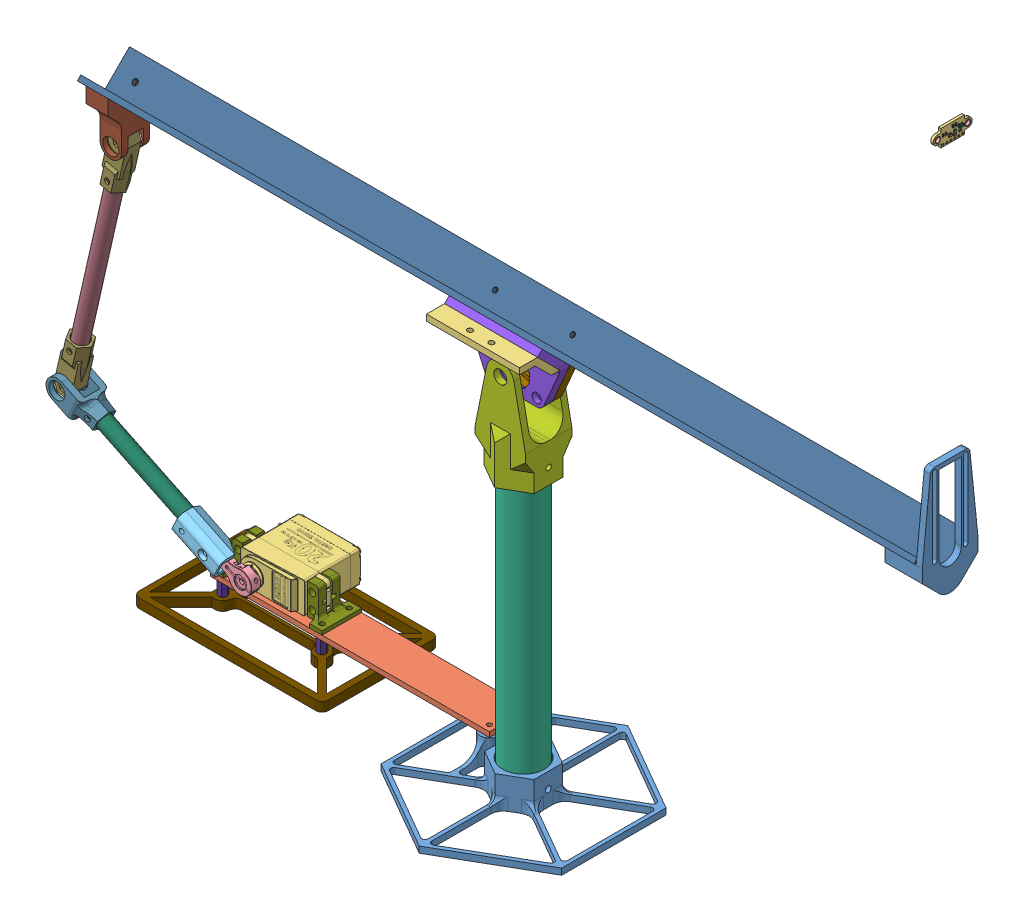
SolidWorks assembly Sistema_barra_bola, configuration Predeterminado. Lengths in mm.
Overall size (579.67 513.66 134.64).
52 component instances, 39 part files, 56 mates.
Components (placement in the parent):
- Soporte_base-1: Soporte_base [Predeterminado] at (0.7319 45.2828 116.0405) x (0 0 1) z (1 0 0) size (134.64 20.58 116.6)
- platina-1: platina [Predeterminado] at (-115.2681 61.2828 99.3405) size (180 3.17 25.4)
- DS3218MG MS24 Digital Servo 270-1: DS3218MG MS24 Digital Servo 270 [Default] at (-179.2681 74.4678 97.7405) x (0 1 0) z (1 0 0) size (20.1 45.99 55.6)
- Servo Arm for DS3218MG-1: Servo Arm for DS3218MG [Default] at (-179.2681 74.4678 118.9404) x (-0.43387 -0.900976 0) z (-0.900976 0.43387 0) size (14.5 6.15 35.53)
- brazo_servo_acople-1: brazo_servo_acople [Predeterminado] at (-206.7479 87.7008 116.0404) x (-0.43387 -0.900976 0) z (0 0 1) size (14.32 30 14.8)
- Tubo_soporte-1: Tubo_soporte [Predeterminado] at (0.7319 45.2828 116.0405) x (0 0 1) z (-1 0 0) size (25.4 200 25.4)
- Articulacion_eje-1: Articulacion_eje [Predeterminado] at (0.7319 250.2828 116.0405) x (0 0 1) z (-1 0 0) size (37.41 69 32.4)
- Soporte_barra_frontal-1: Soporte_barra_frontal [Predeterminado] at (0.7319 299.2828 116.0405) x (1 0 0) z (0 -1 0) size (60 20.96 45.96)
- Soporte_barra_posterior-1: Soporte_barra_posterior [Predeterminado] at (0.7319 299.2828 116.0405) x (-1 0 0) z (0 -1 0) size (60 20.96 45.96)
- Barra-1: Barra [Predeterminado] at (0.7319 299.2828 116.0405) x (1 0 0) z (0 0.707107 0.707107) size (540 25.4 25.4)
- acople_rodamiento_barra-1: acople_rodamiento_barra [Predeterminado] at (-256.5681 282.3833 116.0404) x (0 0 -1) z (1 0 0) size (35.92 41.86 14)
- acople_brazo-1: acople_brazo [Predeterminado] at (-256.5681 282.3833 116.0404) x (0 0 1) z (0.975277 -0.220985 0) size (12.4 33.8 14.32)
- brazo2-1: brazo2 [Predeterminado] at (-287.263 146.9173 116.0404) x (0 0 -1) z (0.975277 -0.220985 0) size (9 120 9)
- acople_brazos-1: acople_brazos [Predeterminado] at (-286.9347 126.3152 116.0404) x (0 0 -1) z (-0.43387 -0.900976 0) size (18 31 14)
- acople_brazo-2: acople_brazo [Predeterminado] at (-291.4396 128.4845 116.0404) x (0 0 -1) z (0.975277 -0.220985 0) size (12.4 33.8 14.32)
- brazo-100mm-1: brazo-100mm [Predeterminado] at (-278.8259 122.4104 116.0404) x (0 0 1) z (0.43387 0.900976 0) size (9 80 9)
- Soporte_servo-1: Soporte_servo [Predeterminado] at (-143.2681 64.4678 99.3404) x (1 0 0) z (0 0 1) size (15 20 25.4)
- Soporte_servo-2: Soporte_servo [Predeterminado] at (-195.2681 64.4678 99.3405) x (-1 0 0) z (0 0 -1) size (15 20 25.4)
- M3_F_TO_F_10MM_STANDOFF.step-1: M3_F_TO_F_10MM_STANDOFF.step [Predeterminado] at (-137.2681 56.2828 108.0405) x (1 0 0) z (0 -1 0) size (5.78 5.78 10)
- M3_F_TO_F_10MM_STANDOFF.step-2: M3_F_TO_F_10MM_STANDOFF.step [Predeterminado] at (-201.2681 56.2828 90.6405) x (1 0 0) z (0 -1 0) size (5.78 5.78 10)
- M3_F_TO_F_10MM_STANDOFF.step-3: M3_F_TO_F_10MM_STANDOFF.step [Predeterminado] at (-137.2681 56.2828 90.6405) x (1 0 0) z (0 -1 0) size (5.78 5.78 10)
- M3_F_TO_F_10MM_STANDOFF.step-4: M3_F_TO_F_10MM_STANDOFF.step [Predeterminado] at (-201.2681 56.2828 108.0405) x (1 0 0) z (0 -1 0) size (5.78 5.78 10)
- base_servo-1: base_servo [Predeterminado] at (-169.2681 45.2828 99.3405) size (122 6 75.4)
- Soporte_sensor-1: Soporte_sensor [Predeterminado] at (272.0319 299.2828 116.0405) x (0 0 -1) z (1 0 0) size (35.92 75.1 24)
- VL53L0X_TOF.step-1: VL53L0X_TOF.step [Predeterminado] at (276.0819 553.4878 116.0405) x (0 0 1) z (-1 0 0) size (25.2 10.9 3.8)
  - Trous.step-1: Trous.step [Predeterminado] at origin size (14.1 1.4 1.7)
    - Trou1.step-1: Trou1.step [Predeterminado] at (-6.35 -4.3 0) size (1.4 1.4 1.7)
    - Trou1.step-2: Trou1.step [Predeterminado] at (-3.81 -4.3 0) size (1.4 1.4 1.7)
    - Trou1.step-3: Trou1.step [Predeterminado] at (-1.27 -4.3 0) size (1.4 1.4 1.7)
    - Trou1.step-4: Trou1.step [Predeterminado] at (1.27 -4.3 0) size (1.4 1.4 1.7)
    - Trou1.step-5: Trou1.step [Predeterminado] at (3.81 -4.3 0) size (1.4 1.4 1.7)
    - Trou1.step-6: Trou1.step [Predeterminado] at (6.35 -4.3 0) size (1.4 1.4 1.7)
  - PCB_pink.step-1: PCB_pink.step [Predeterminado] at origin size (25.2 10.9 1.6)
  - TrouFix01.step-1: TrouFix01.step [Predeterminado] at (-9.7 0 0) size (3.8 3.8 1.7)
  - TrouFix01.step-2: TrouFix01.step [Predeterminado] at (9.7 0 0) size (3.8 3.8 1.7)
  - Text_VIN.step-1: Text_VIN.step [Predeterminado] at (-5.9 -3.3 0) size (0.93 2.06 0.05)
  - Text_GND.step-1: Text_GND.step [Predeterminado] at (-3.45 -3.3 0) size (0.97 2.76 0.05)
  - Text_SCL.step-1: Text_SCL.step [Predeterminado] at (-0.85 -3.3 0) size (0.97 2.43 0.05)
  - Text_SDA.step-1: Text_SDA.step [Predeterminado] at (1.65 -3.3 0) size (0.97 2.62 0.05)
  - Text_GPIO1.step-1: Text_GPIO1.step [Predeterminado] at (4.25 -3.3 0) size (0.97 3.67 0.05)
  - Text_XSHUT.step-1: Text_XSHUT.step [Predeterminado] at (6.95 -3.3 0) size (0.97 4.38 0.05)
  - Text_VL53L0X-V2.step-1: Text_VL53L0X-V2.step [Predeterminado] at (-4.15 3.85 0) x (0 -1 0) z (0 0 1) size (0.96 7.32 0.05)
  - VL53L0X.step-1: VL53L0X.step [Predeterminado] at (2.25 -1.4 0) size (4.4 2.4 1)
  - C_0603_1608Metric.step-1: C_0603_1608Metric.step [Predeterminado] at (-4.4 -1.3 -1.6) x (1 0 0) z (0 0 -1) size (1.6 0.8 0.8)
  - R_Array_Convex_4x0603.step-1: R_Array_Convex_4x0603.step [Predeterminado] at (-1.15 -0.95 -1.6) x (1 0 0) z (0 0 -1) size (1.6 3.2 0.5)
  - SOT_23.step-1: SOT_23.step [Predeterminado] at (-4.85 1.2 -1.6) x (0 -1 0) z (0 0 -1) size (2.5 3 1.2)
  - C_0603_1608Metric001.step-1: C_0603_1608Metric001.step [Predeterminado] at (-1.7 3.3 -1.6) x (0 1 0) z (0 0 -1) size (1.6 0.8 0.8)
  - C_0603_1608Metric002.step-1: C_0603_1608Metric002.step [Predeterminado] at (0.15 3.25 -1.6) x (0 1 0) z (0 0 -1) size (1.6 0.8 0.8)
  - R_0603_1608Metric.step-1: R_0603_1608Metric.step [Predeterminado] at (6.4 1.1 -1.6) x (0 -1 0) z (0 0 -1) size (1.6 0.8 0.45)
  - R_0603_1608Metric001.step-1: R_0603_1608Metric001.step [Predeterminado] at (4.55 1.05 -1.6) x (0 -1 0) z (0 0 -1) size (1.6 0.8 0.45)
  - SOT_363_SC_70_6.step-1: SOT_363_SC_70_6.step [Predeterminado] at (2.1 -0.8 -1.6) x (0 -1 0) z (0 0 -1) size (2 2 1.05)
- Soporte_BMI160-1: Soporte_BMI160 [Predeterminado] at (0.7319 299.8161 122.5738) x (0 0 -1) z (1 0 0) size (26.08 14.42 60)
Mates (geometry in assembly coordinates):
- Concéntrica1: concentric aligned: cylinder of Soporte_base-1 through (-29.2681 61.2828 90.6405) axis (0 -1 0) radius 1.8; cylinder of platina-1 through (-29.2681 64.4578 90.6405) axis (0 -1 0) radius 1.5
- Concéntrica2: concentric aligned: cylinder of Soporte_base-1 through (-29.2681 61.2828 108.0405) axis (0 -1 0) radius 1.8; cylinder of platina-1 through (-29.2681 64.4578 108.0405) axis (0 -1 0) radius 1.5
- Coincidente1: coincident anti-aligned: plane of Soporte_base-1 through (0.7319 61.2828 116.0405) normal (0 1 0); plane of platina-1 through (-115.2681 61.2828 99.3405) normal (0 -1 0)
- Concéntrica12: concentric aligned: cylinder of DS3218MG MS24 Digital Servo 270-1 through (-179.2681 74.4678 112.1405) axis (0 0 1) radius 1.25; cylinder of Servo Arm for DS3218MG-1 through (-179.2681 74.4678 112.9405) axis (0 0 1) radius 1.5
- Concéntrica13: concentric aligned: circle of Servo Arm for DS3218MG-1; cylinder of brazo_servo_acople-1 through (-203.7407 73.3091 97.629) axis (0 0 1) radius 1.5
- Concéntrica14: concentric anti-aligned: circle of Servo Arm for DS3218MG-1; cylinder of brazo_servo_acople-1 through (-199.7452 73.4982 124.6405) axis (0 0 -1) radius 1.5
- Concéntrica15: concentric anti-aligned: cylinder of Soporte_base-1 through (-20.5421 55.2828 116.0405) axis (1 0 0) radius 1.9; cylinder of Tubo_soporte-1 through (13.4319 55.2828 116.0405) axis (-1 0 0) radius 1.5
- Concéntrica16: concentric aligned: cylinder of Soporte_base-1 through (0.7319 65.2828 116.0405) axis (0 -1 0) radius 13.5; cylinder of Tubo_soporte-1 through (0.7319 245.2828 116.0405) axis (0 -1 0) radius 12.7
- Concéntrica17: concentric aligned: cylinder of Tubo_soporte-1 through (13.4319 235.2828 116.0405) axis (-1 0 0) radius 1.5; cylinder of Articulacion_eje-1 through (21.7402 235.2828 116.0405) axis (-1 0 0) radius 1.7
- Concéntrica18: concentric anti-aligned: cylinder of Tubo_soporte-1 through (0.7319 245.2828 116.0405) axis (0 -1 0) radius 12.7; cylinder of Articulacion_eje-1 through (0.7319 225.2828 116.0405) axis (0 1 0) radius 13.1
- Coincidente5: coincident anti-aligned: plane of Soporte_barra_frontal-1 through (-31.8693 291.0412 116.0405) normal (0 0 -1); plane of Soporte_barra_posterior-1 through (26.0862 306.5703 116.0405) normal (0 0 1)
- Concéntrica19: concentric anti-aligned: cylinder of Soporte_barra_frontal-1 through (0.7319 285.2828 154.0444) axis (0 0 -1) radius 10; cylinder of Soporte_barra_posterior-1 through (0.7319 285.2828 78.0366) axis (0 0 1) radius 10
- Concéntrica20: concentric anti-aligned: cylinder of Soporte_barra_posterior-1 through (20.6146 307.672 100.5602) axis (-0.183013 0.683013 0.707107) radius 1.75; cylinder of Barra-1 through (17.4454 319.4998 112.8053) axis (0.183013 -0.683013 -0.707107) radius 1.5
- Concéntrica21: concentric aligned: cylinder of Soporte_barra_frontal-1 through (-28.9535 299.4778 126.6065) axis (0.183013 -0.683013 0.707107) radius 3; cylinder of Barra-1 through (-30.8509 306.5588 119.2757) axis (0.183013 -0.683013 0.707107) radius 1.5
- Ancho2: width anti-aligned: plane of Soporte_barra_frontal-1 through (-24.6224 263.9952 122.0405) normal (0 0 1); plane of Articulacion_eje-1 through (33.3331 279.5244 110.0405) normal (0 0 -1); plane of Soporte_barra_posterior-1 through (0.7319 250.2828 127.0405) normal (0 0 -1); plane of Articulacion_eje-1 through (0.7319 250.2828 105.0405) normal (0 0 1)
- Concéntrica22: concentric aligned: cylinder of Articulacion_eje-1 through (0.7319 285.2828 101.0405) axis (0 0 1) radius 4.2; cylinder of Soporte_barra_posterior-1 through (0.7319 285.2828 111.6405) axis (0 0 1) radius 12.5
- Ancho3: width anti-aligned: plane of acople_rodamiento_barra-1 through (-247.0504 215.8879 111.0405) normal (0 0 1); plane of acople_brazo-1 through (-247.0504 215.8879 121.0405) normal (0 0 -1); plane of acople_rodamiento_barra-1 through (-247.0504 215.8879 111.0405) normal (0 0 -1); plane of acople_brazo-1 through (-247.0504 215.8879 121.0405) normal (0 0 1)
- Concéntrica23: concentric aligned: cylinder of acople_rodamiento_barra-1 through (-247.0504 215.8879 122.0405) axis (0 0 1) radius 5.2; circle of acople_brazo-1
- Concéntrica24: concentric anti-aligned: cylinder of Barra-1 through (-255.2355 246.4352 119.2757) axis (0.183013 -0.683013 0.707107) radius 1.75; cylinder of acople_rodamiento_barra-1 through (-251.5875 232.8206 133.3705) axis (-0.183013 0.683013 -0.707107) radius 1.7
- Concéntrica25: concentric anti-aligned: cylinder of Barra-1 through (-255.2355 246.4352 112.8053) axis (0.183013 -0.683013 -0.707107) radius 1.75; cylinder of acople_rodamiento_barra-1 through (-251.5875 232.8206 98.7105) axis (-0.183013 0.683013 0.707107) radius 1.7
- Concéntrica26: concentric anti-aligned: cylinder of acople_brazo-1 through (-255.6196 193.577 109.8405) axis (0 0 1) radius 1.7; cylinder of brazo2-1 through (-255.6196 193.577 120.5405) axis (0 0 -1) radius 1.5
- Concéntrica27: concentric anti-aligned: cylinder of acople_brazo-1 through (-257.4123 188.9094 116.0405) axis (0.358545 0.933512 0) radius 5; cylinder of brazo2-1 through (-253.8269 198.2446 116.0405) axis (-0.358545 -0.933512 0) radius 4.5
- Concéntrica28: concentric aligned: cylinder of brazo2-1 through (-295.0596 90.8906 120.5405) axis (0 0 -1) radius 1.5; cylinder of acople_brazo-2 through (-295.0596 90.8906 122.2405) axis (0 0 -1) radius 1.7
- Concéntrica29: concentric aligned: cylinder of brazo2-1 through (-253.8269 198.2446 116.0405) axis (-0.358545 -0.933512 0) radius 4.5; cylinder of acople_brazo-2 through (-293.2668 95.5582 116.0405) axis (-0.358545 -0.933512 0) radius 5
- Ancho4: width anti-aligned: plane of acople_brazos-1 through (-298.6344 68.8162 111.0405) normal (0 0 1); plane of acople_brazo-2 through (-298.6344 68.8162 121.0405) normal (0 0 -1); plane of acople_brazos-1 through (-303.6288 68.5797 111.0405) normal (0 0 -1); plane of acople_brazo-2 through (-303.6288 68.5797 121.0405) normal (0 0 1)
- Concéntrica30: concentric anti-aligned: cylinder of acople_brazos-1 through (-303.6288 68.5797 122.0405) axis (0 0 1) radius 5.2; circle of acople_brazo-2
- Concéntrica31: concentric anti-aligned: cylinder of acople_brazos-1 through (-284.65 69.4783 125.0405) axis (0 0 -1) radius 1.7; cylinder of brazo-100mm-1 through (-284.65 69.4783 111.5405) axis (0 0 1) radius 1.5
- Concéntrica32: concentric aligned: cylinder of acople_brazos-1 through (-279.6556 69.7147 116.0405) axis (-0.998881 -0.047294 0) radius 5; cylinder of brazo-100mm-1 through (-209.734 73.0253 116.0405) axis (-0.998881 -0.047294 0) radius 4.5
- Concéntrica33: concentric anti-aligned: cylinder of brazo_servo_acople-1 through (-214.7284 72.7888 124.6405) axis (0 0 -1) radius 1.5; cylinder of brazo-100mm-1 through (-214.7284 72.7888 111.5405) axis (0 0 1) radius 1.5
- Concéntrica34: concentric anti-aligned: cylinder of brazo_servo_acople-1 through (-219.7228 72.5524 116.0405) axis (0.998881 0.047294 0) radius 5; cylinder of brazo-100mm-1 through (-209.734 73.0253 116.0405) axis (-0.998881 -0.047294 0) radius 4.5
- Coincidente7: coincident anti-aligned: plane of Servo Arm for DS3218MG-1 through (-179.2681 74.4678 114.9405) normal (0 0 -1); plane of brazo_servo_acople-1 through (-209.734 73.0253 114.9405) normal (0 0 1)
- Concéntrica38: concentric anti-aligned: cylinder of DS3218MG MS24 Digital Servo 270-1 through (-193.2681 79.4678 91.3765) axis (0 0 1) radius 2.25; cylinder of Soporte_servo-2 through (-193.2681 79.4678 112.563) axis (0 0 -1) radius 2.2
- Concéntrica39: concentric aligned: cylinder of DS3218MG MS24 Digital Servo 270-1 through (-145.2681 69.4678 91.3765) axis (0 0 1) radius 2.25; cylinder of Soporte_servo-1 through (-145.2681 69.4678 86.1179) axis (0 0 1) radius 2.2
- Concéntrica40: concentric aligned: cylinder of platina-1 through (-201.2681 64.4578 108.0405) axis (0 -1 0) radius 1.5; cylinder of Soporte_servo-2 through (-201.2681 75.895 108.0405) axis (0 -1 0) radius 1.6
- Concéntrica41: concentric aligned: cylinder of platina-1 through (-137.2681 64.4578 90.6405) axis (0 -1 0) radius 1.5; cylinder of Soporte_servo-1 through (-137.2681 75.895 90.6405) axis (0 -1 0) radius 1.6
- Coincidente8: coincident anti-aligned: plane of platina-1 through (-115.2681 64.4578 99.3405) normal (0 1 0); plane of DS3218MG MS24 Digital Servo 270-1 through (-169.099 64.4578 93.2687) normal (0 -1 0)
- Ancho5: width anti-aligned: plane of DS3218MG MS24 Digital Servo 270-1 through (-152.2681 83.4678 97.7405) normal (0 0 -1); plane of Soporte_servo-2 through (-179.2681 74.4678 100.9405) normal (0 0 1); plane of DS3218MG MS24 Digital Servo 270-1 through (-190.2681 64.4678 97.3405) normal (0 0 1); plane of Soporte_servo-2 through (-190.2681 64.4678 101.3405) normal (0 0 -1)
- Coincidente9: coincident aligned: plane of M3_F_TO_F_10MM_STANDOFF.step-2 through (-201.2681 61.2828 90.6405) normal (0 1 0); plane of M3_F_TO_F_10MM_STANDOFF.step-4 through (-201.2681 61.2828 108.0405) normal (0 1 0)
- Coincidente10: coincident aligned: plane of M3_F_TO_F_10MM_STANDOFF.step-2 through (-201.2681 61.2828 90.6405) normal (0 1 0); plane of M3_F_TO_F_10MM_STANDOFF.step-3 through (-137.2681 61.2828 90.6405) normal (0 1 0)
- Coincidente11: coincident aligned: plane of M3_F_TO_F_10MM_STANDOFF.step-1 through (-137.2681 61.2828 108.0405) normal (0 1 0); plane of M3_F_TO_F_10MM_STANDOFF.step-2 through (-201.2681 61.2828 90.6405) normal (0 1 0)
- Coincidente12: coincident anti-aligned: plane of platina-1 through (-115.2681 61.2828 99.3405) normal (0 -1 0); plane of M3_F_TO_F_10MM_STANDOFF.step-2 through (-201.2681 61.2828 90.6405) normal (0 1 0)
- Concéntrica42: concentric aligned: cylinder of platina-1 through (-201.2681 64.4578 90.6405) axis (0 -1 0) radius 1.5; cylinder of M3_F_TO_F_10MM_STANDOFF.step-2 through (-201.2681 51.2828 90.6405) axis (0 -1 0) radius 1.25
- Concéntrica43: concentric aligned: cylinder of platina-1 through (-137.2681 64.4578 90.6405) axis (0 -1 0) radius 1.5; cylinder of M3_F_TO_F_10MM_STANDOFF.step-3 through (-137.2681 51.2828 90.6405) axis (0 -1 0) radius 1.25
- Concéntrica44: concentric aligned: cylinder of platina-1 through (-137.2681 64.4578 108.0405) axis (0 -1 0) radius 1.5; cylinder of M3_F_TO_F_10MM_STANDOFF.step-1 through (-137.2681 51.2828 108.0405) axis (0 -1 0) radius 1.25
- Concéntrica45: concentric aligned: cylinder of platina-1 through (-201.2681 64.4578 108.0405) axis (0 -1 0) radius 1.5; cylinder of M3_F_TO_F_10MM_STANDOFF.step-4 through (-201.2681 51.2828 108.0405) axis (0 -1 0) radius 1.25
- Concéntrica46: concentric aligned: cylinder of M3_F_TO_F_10MM_STANDOFF.step-2 through (-201.2681 51.2828 90.6405) axis (0 -1 0) radius 1.25; cylinder of base_servo-1 through (-201.2681 51.2828 90.6405) axis (0 -1 0) radius 1.6
- Concéntrica47: concentric aligned: cylinder of M3_F_TO_F_10MM_STANDOFF.step-1 through (-137.2681 51.2828 108.0405) axis (0 -1 0) radius 1.25; cylinder of base_servo-1 through (-137.2681 51.2828 108.0405) axis (0 -1 0) radius 1.6
- Coincidente13: coincident anti-aligned: plane of M3_F_TO_F_10MM_STANDOFF.step-4 through (-201.2681 51.2828 108.0405) normal (0 -1 0); plane of base_servo-1 through (-169.2681 51.2828 99.3405) normal (0 1 0)
- Concéntrica48: concentric anti-aligned: cylinder of Barra-1 through (241.83 379.6234 112.8053) axis (0.183013 -0.683013 -0.707107) radius 1.75; cylinder of Soporte_sensor-1 through (245.3467 366.4987 99.2176) axis (-0.183013 0.683013 0.707107) radius 1.8
- Concéntrica49: concentric aligned: cylinder of Barra-1 through (241.83 379.6234 119.2757) axis (0.183013 -0.683013 0.707107) radius 1.75; cylinder of Soporte_sensor-1 through (243.6829 372.7081 126.4349) axis (0.183013 -0.683013 0.707107) radius 3.2
- Coincidente14: coincident anti-aligned: plane of Soporte_sensor-1; plane of VL53L0X_TOF.step-1/TrouFix01.step-2
- Ancho6: width aligned: plane of Soporte_sensor-1 through (263.0278 370.0586 124.5405) normal (0 0 1); plane of VL53L0X_TOF.step-1/PCB_pink.step-1 through (263.0278 370.0586 107.5405) normal (0 0 -1); plane of Soporte_sensor-1 through (212.9479 557.1527 123.6905) normal (0 0 1); plane of VL53L0X_TOF.step-1/PCB_pink.step-1 through (212.495 558.843 108.3905) normal (0 0 -1)
- Paralelo1: parallel aligned: plane of Soporte_base-1 through (0.7319 45.2828 116.0405) normal (0 -1 0); plane of Soporte_barra_frontal-1 through (-29.2681 271.2828 116.0405) normal (0 -1 0)
- Concéntrica50: concentric aligned: cylinder of Soporte_barra_frontal-1 through (-28.9535 299.4778 126.6065) axis (0.183013 -0.683013 0.707107) radius 3; cylinder of Soporte_BMI160-1 through (-29.5193 301.5891 124.4207) axis (0.183013 -0.683013 0.707107) radius 1.8
- Concéntrica51: concentric anti-aligned: cylinder of Soporte_barra_frontal-1 through (20.6146 307.672 131.5207) axis (-0.183013 0.683013 -0.707107) radius 1.75; cylinder of Soporte_BMI160-1 through (18.777 314.53 124.4207) axis (0.183013 -0.683013 0.707107) radius 1.8
- Coincidente15: coincident anti-aligned: plane of Soporte_barra_frontal-1; plane of Soporte_BMI160-1
